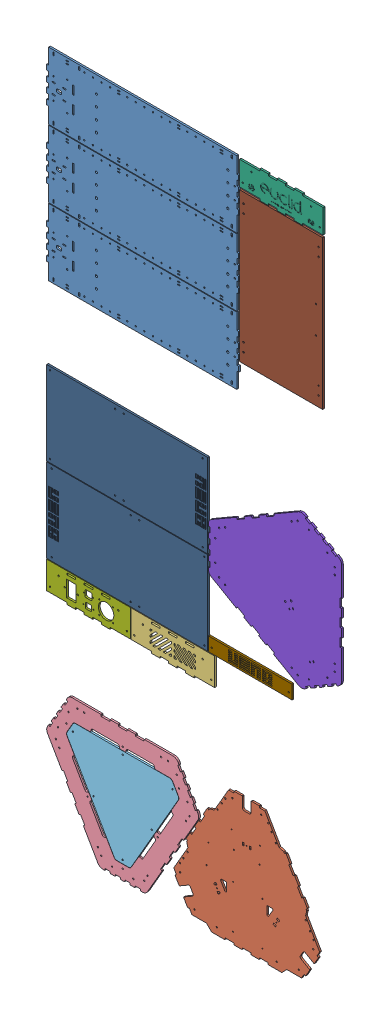
SolidWorks assembly acrylic-lasercut-layout-900x600, configuration Default. Lengths in mm.
Overall size (1073.15 2208.42 216.11).
14 component instances, 11 part files, 41 mates.
Components (placement in the parent):
- acrylic-wall-1: acrylic-wall [Default] at (-350 -197.4774 220) x (0 0 -1) z (0 -1 0) size (5 560 195.39)
- acrylic-wall-2: acrylic-wall [Default] at (-350 -0.0864 220) x (0 0 -1) z (0 -1 0) size (5 560 195.39)
- acrylic-wall-3: acrylic-wall [Default] at (-350 197.3045 220) x (0 0 -1) z (0 -1 0) size (5 560 195.39)
- acrylic-base-1: acrylic-base [Default] at (138.2307 -1533.4225 -15) x (0 1 0) z (-1 0 0) size (388.46 5 425.46)
- acrylic-bay-cover-1: acrylic-bay-cover [Default] at (-77.3463 -990.7495 168.4567) x (0.866025 0 -0.5) z (0.5 0 0.866025) size (213.61 85 126.21)
- acrylic-bottom-1: acrylic-bottom [Default] at (-223.3543 -1481.8792 -90) x (-0.866025 0.5 0) z (-0.5 -0.866025 0) size (388.46 5 443.29)
- acrylic-electronics-cover-1: acrylic-electronics-cover [Default] at (-223.3543 -1481.8792 -90) x (-0.866025 0.5 0) z (-0.5 -0.866025 0) size (285.46 5 326.68)
- acrylic-pscover-1: acrylic-pscover [Default] at (238.8846 310 168.4567) x (0.866025 0 -0.5) z (0.5 0 0.866025) size (213.61 80 126.21)
- acrylic-switch-cover-1: acrylic-switch-cover [Default] at (-323.1154 -990.7495 168.4567) x (0.866025 0 -0.5) z (0.5 0 0.866025) size (213.61 85 126.21)
- acrylic-top-1: acrylic-top [Default] at (246.5 -733.0996 -460) x (0.5 -0.866025 0) z (-0.866025 -0.5 0) size (388.46 5 443.29)
- acrylic-nameplate-1: acrylic-nameplate [Default] at (148.3846 -538.9995 168.4567) x (-0.866025 0 -0.5) z (-0.5 0 0.866025) size (213.61 40 126.21)
- acrylic-window-bl-1: acrylic-window-bl [Default] at (-435.25 -631.0958 -163.4567) x (0 0.866025 0.5) z (0 0.5 -0.866025) size (213.61 469.5 126.21)
- acrylic-window-bl-2: acrylic-window-bl [Default] at (14.75 -876.865 168.4567) x (0 0.866025 -0.5) z (0 0.5 0.866025) size (213.61 469.5 126.21)
- acrylic-door-1: acrylic-door [Default] at (238.3846 198.5 168.4567) x (-0.866025 0 -0.5) z (-0.5 0 0.866025) size (212.74 433.75 125.71)
Mates (geometry in assembly coordinates):
- Coincident1: coincident anti-aligned: plane of acrylic-wall-3 through (-440 254.9896 0) normal (0 0 -1); plane of assembly through (0 0 0) normal (0 0 1)
- Coincident2: coincident anti-aligned: plane of acrylic-wall-2 through (-440 57.5986 0) normal (0 0 -1); plane of assembly through (0 0 0) normal (0 0 1)
- Coincident3: coincident anti-aligned: plane of acrylic-wall-1 through (-440 -139.7923 0) normal (0 0 -1); plane of assembly through (0 0 0) normal (0 0 1)
- Coincident4: coincident anti-aligned: plane of acrylic-base-1 through (133.8222 -1541.0583 0) normal (0 0 -1); plane of assembly through (0 0 0) normal (0 0 1)
- Coincident5: coincident anti-aligned: plane of acrylic-bay-cover-1 through (-77.3463 -990.7495 0) normal (0 0 -1); plane of assembly through (0 0 0) normal (0 0 1)
- Coincident6: coincident anti-aligned: plane of acrylic-pscover-1 through (238.8846 310 0) normal (0 0 -1); plane of assembly through (0 0 0) normal (0 0 1)
- Coincident7: coincident anti-aligned: plane of acrylic-switch-cover-1 through (-323.1154 -990.7495 0) normal (0 0 -1); plane of assembly through (0 0 0) normal (0 0 1)
- Coincident8: coincident anti-aligned: plane of acrylic-bottom-1 through (-223.3543 -1481.8792 0) normal (0 0 -1); plane of assembly through (0 0 0) normal (0 0 1)
- Coincident9: coincident anti-aligned: plane of acrylic-electronics-cover-1 through (-223.3543 -1481.8792 0) normal (0 0 -1); plane of assembly through (0 0 0) normal (0 0 1)
- Coincident10: coincident anti-aligned: plane of acrylic-top-1 through (43.5 -675.4146 0) normal (0 0 -1); plane of assembly through (0 0 0) normal (0 0 1)
- Coincident11: coincident anti-aligned: plane of acrylic-nameplate-1 through (148.3846 -538.9995 0) normal (0 0 -1); plane of assembly through (0 0 0) normal (0 0 1)
- Coincident13: coincident anti-aligned: plane of acrylic-door-1 through (238.3846 198.5 0) normal (0 0 -1); plane of assembly through (0 0 0) normal (0 0 1)
- Coincident14: coincident anti-aligned: plane of acrylic-window-bl-2 through (14.75 -876.865 0) normal (0 0 -1); plane of assembly through (0 0 0) normal (0 0 1)
- Coincident20: coincident aligned: plane of acrylic-wall-2 through (115 51.1561 5) normal (1 0 0); plane of acrylic-wall-3 through (115 146.062 5) normal (1 0 0)
- Distance1: distance = 5 mm: line of assembly; plane of acrylic-wall-3 through (-440 295 5) normal (0 1 0)
- Distance2: distance = 5 mm: plane of acrylic-wall-3 through (-445 248.5471 5) normal (-1 0 0); line of assembly
- Distance3: distance = 2 mm anti-aligned: plane of acrylic-wall-3 through (-440 99.6091 5) normal (0 -1 0); plane of acrylic-wall-2 through (-440 97.6091 5) normal (0 1 0)
- Coincident30: coincident anti-aligned: plane of acrylic-window-bl-1 through (-435.25 -631.0958 0) normal (0 0 -1); plane of assembly through (0 0 0) normal (0 0 1)
- Distance12: distance = 2 mm anti-aligned: plane of acrylic-pscover-1 through (176.4846 215 5) normal (0 -1 0); plane of acrylic-door-1 through (238.3846 213 455.482) normal (0 1 0)
- Coincident34: coincident aligned: plane of acrylic-pscover-1 through (117 220.25 5) normal (-1 0 0); plane of acrylic-door-1 through (117 -220.75 110.3386) normal (-1 0 0)
- Distance15: distance = 0.5 mm anti-aligned: plane of acrylic-bottom-1 through (-369.1603 -1378.4225 -555) normal (0.866025 -0.5 0); plane of acrylic-electronics-cover-1 through (-368.7272 -1378.6725 -555) normal (-0.866025 0.5 0)
- Distance16: distance = 0.5 mm anti-aligned: plane of acrylic-bottom-1 through (-77.5484 -1378.4225 -555) normal (-0.866025 -0.5 0); plane of acrylic-electronics-cover-1 through (-77.9814 -1378.6725 -555) normal (0.866025 0.5 0)
- Coincident43: coincident aligned: plane of acrylic-switch-cover-1 through (-445 -1080.4995 5) normal (-1 0 0); plane of acrylic-window-bl-2 through (-445 -754.9804 5) normal (-1 0 0)
- Distance21: distance = 2 mm anti-aligned: plane of acrylic-switch-cover-1 through (-201.2309 -1000.7495 248.8204) normal (0 1 0); plane of acrylic-window-bl-2 through (-445 -998.7495 5) normal (0 -1 0)
- Distance22: distance = 2 mm anti-aligned: plane of acrylic-bay-cover-1 through (-199.2309 -1080.4995 5) normal (-1 0 0); plane of acrylic-switch-cover-1 through (-201.2309 -1080.4995 5) normal (1 0 0)
- Distance23: distance = 2 mm anti-aligned: plane of acrylic-bay-cover-1 through (-199.2309 -1000.7495 -243.8204) normal (0 1 0); plane of acrylic-window-bl-2 through (-445 -998.7495 5) normal (0 -1 0)
- Distance24: distance = 2 mm anti-aligned: plane of acrylic-wall-1 through (-440 -99.7819 5) normal (0 1 0); plane of acrylic-wall-2 through (-440 -97.7819 5) normal (0 -1 0)
- Coincident45: coincident aligned: plane of acrylic-wall-1 through (-439.5 -139.7923 5) normal (-1 0 0); plane of acrylic-wall-2 through (-439.5 -57.7715 5) normal (-1 0 0)
- Coincident46: coincident aligned: plane of acrylic-wall-3 through (-440 295 5) normal (0 1 0); plane of acrylic-pscover-1 through (360.7691 295 5) normal (0 1 0)
- Distance25: distance = 2 mm anti-aligned: plane of acrylic-wall-3 through (115 203.7471 5) normal (1 0 0); plane of acrylic-door-1 through (117 -220.75 110.3386) normal (-1 0 0)
- Distance26: distance = 2 mm anti-aligned: plane of acrylic-top-1 through (26.5 -733.0996 5) normal (-1 0 0); plane of acrylic-window-bl-1 through (24.5 -509.2113 0) normal (1 0 0)
- Distance27: distance = 5 mm: plane of acrylic-window-bl-1 through (-445 -509.2113 -105.5551) normal (-1 0 0); line of assembly
- Distance28: distance = 5 mm: plane of acrylic-window-bl-1 through (24.5 -509.2113 0) normal (0 1 0); line of assembly
- Coincident51: coincident aligned: plane of acrylic-window-bl-1 through (-445 -509.2113 -105.5551) normal (-1 0 0); plane of acrylic-window-bl-2 through (-445 -754.9804 5) normal (-1 0 0)
- Distance29: distance = 2 mm anti-aligned: plane of acrylic-window-bl-1 through (24.5 -752.9804 0) normal (0 -1 0); plane of acrylic-window-bl-2 through (-445 -754.9804 5) normal (0 1 0)
- Distance30: distance = 2 mm anti-aligned: plane of acrylic-nameplate-1 through (26.5 -998.7495 5) normal (-1 0 0); plane of acrylic-window-bl-2 through (24.5 -754.9804 110.5551) normal (1 0 0)
- Coincident54: coincident aligned: plane of acrylic-nameplate-1 through (26.5 -998.7495 5) normal (0 -1 0); plane of acrylic-window-bl-2 through (-445 -998.7495 5) normal (0 -1 0)
- Distance31: distance = 5 mm: plane of ? through (-380.1299 -1313.4225 0) normal (0 1 0)
- Distance32: distance = 5 mm: cylinder of ? through (-428 -1430.3359 0) axis (0 0 1) radius 17
- Distance33: distance = 2 mm anti-aligned: plane of acrylic-base-1 through (-1.4071 -1438.3688 34.4365) normal (-0.866025 0.5 0); plane of acrylic-bottom-1 through (-155.8543 -1701.8792 0) normal (0.866025 -0.5 0)
- Coincident58: coincident aligned: plane of acrylic-base-1 through (255.3652 -1701.8792 239.7489) normal (0 -1 0); plane of acrylic-bottom-1 through (-155.8543 -1701.8792 0) normal (0 -1 0)
